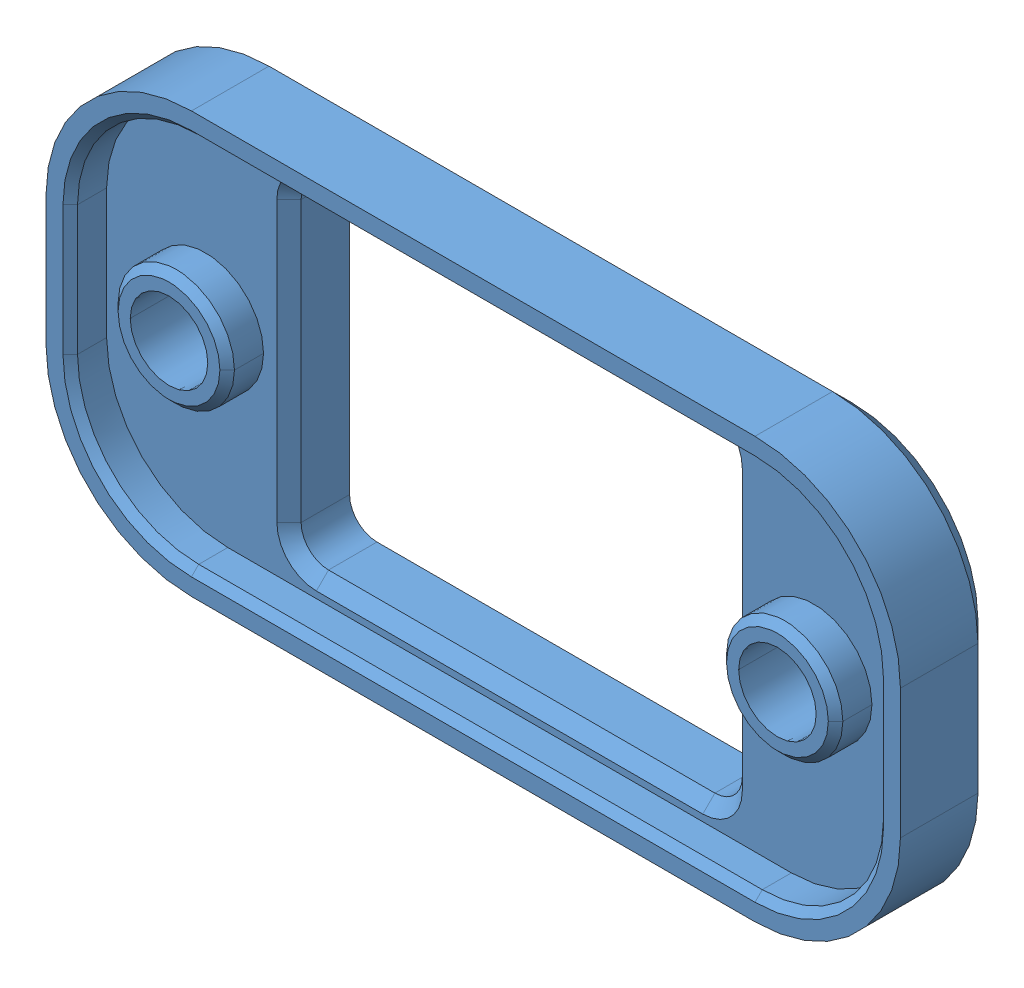
SolidWorks assembly YC_XC_DD000261_ASM_8_ASM.stp, configuration Default. Lengths in mm.
Overall size (35.25 17.35 4).
6 component instances, 1 part files, 0 mates.
Components (placement in the parent):
- LINE_VT_ASM_2_ASM.stp-1: LINE_VT_ASM_2_ASM.stp [Default] at (2.2505 7.8885 -357.5)
  - DD261LINE_ASM_2_ASM.stp-1: DD261LINE_ASM_2_ASM.stp [Default] at origin
    - LINE4A1_ASM_9_ASM_3.stp-1: LINE4A1_ASM_9_ASM_3.stp [Default] at (1.5495 0.4519 132.5) (suppressed, hidden)
- DD261_PLUG_VT1_ASM_4_ASM.stp-1: DD261_PLUG_VT1_ASM_4_ASM.stp [Default] at (3.8 8.3405 10.4) x (1 0 0) z (0 1 0)
  - DD261_PLUG_7_ASM_3_ASM.stp-1: DD261_PLUG_7_ASM_3_ASM.stp [Default] at origin (suppressed, hidden)
- YC_WJ_ZZ004043_1.stp-1: YC_WJ_ZZ004043_1.stp [Default] at (35.8 -20.0095 68.1) x (0 0 -1) z (0 1 0) size (4 35.25 17.35)
